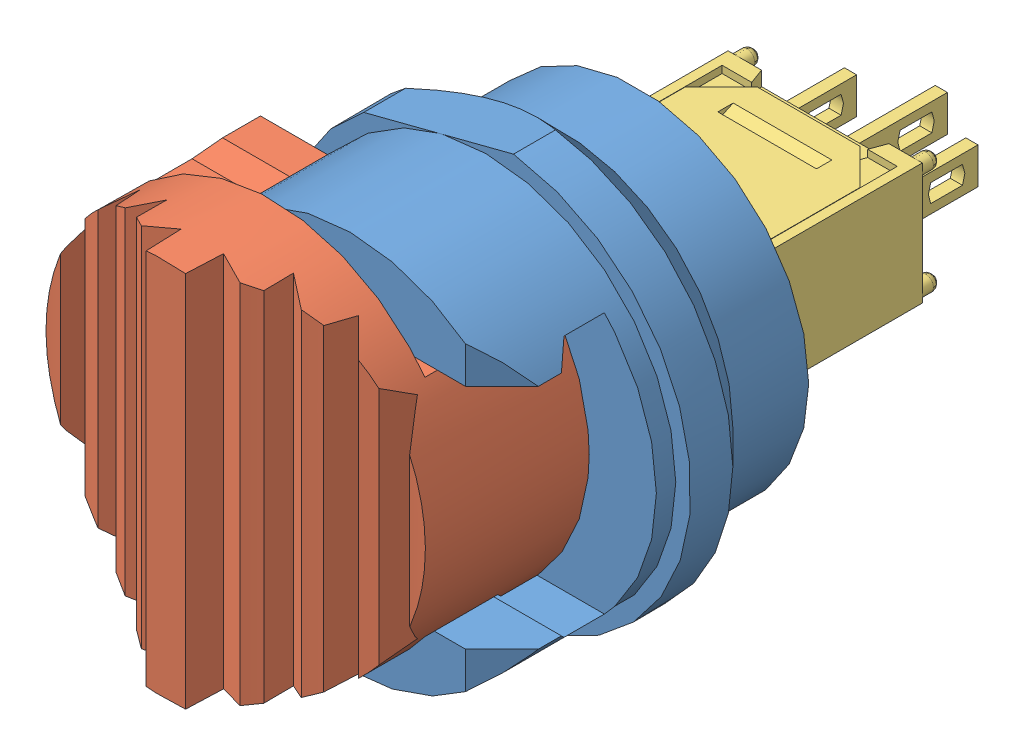
SolidWorks assembly DISPENSE Switch, configuration Default. Lengths in mm.
Overall size (19.33 17.7 29.64).
4 component instances, 4 part files, 9 mates.
Components (placement in the parent):
- SPD BRK Switch Body-1: SPD BRK Switch Body [Default] at origin size (17.14 17.7 12.04)
- SPD BRK Switch Cap-1: SPD BRK Switch Cap [Default] at (-2.8116 0 0) size (15.88 15.88 9.81)
- 200MSPxT1B1M1QE-1: 200MSPxT1B1M1QE [200MSP4T1B1M2REH] at (0 0 -12.6025) size (8.13 6 27)
- HDW211048UNSHEXNUT-1: HDW211048UNSHEXNUT [Default] at (0 0 -0.2675) x (-0.866025 -0.5 0) z (0.5 -0.866025 0) size (7 1.32 8.08)
Mates (geometry in assembly coordinates):
- Concentric1: concentric aligned: cylinder of SPD BRK Switch Body-1 through (0 0 -9.3345) axis (0 0 1) radius 7.1501; cylinder of 200MSPxT1B1M1QE-1 through (0 0 -5.022) axis (0 0 1) radius 2.3
- Coincident1: coincident anti-aligned: plane of SPD BRK Switch Body-1 through (-4.0005 0 -4.7625) normal (0 0 -1); plane of 200MSPxT1B1M1QE-1 through (3.3 -3.3 -4.7625) normal (0 0 1)
- Perpendicular1: perpendicular: plane of SPD BRK Switch Cap-1 through (-3.6371 0 12.1793) normal (-0.999133 0 0.041631); plane of 200MSPxT1B1M1QE-1 through (-4.065 2.54 -12.6025) normal (0 1 0)
- Width1: width anti-aligned: plane of SPD BRK Switch Cap-1 through (-2.8116 4.699 7.7343) normal (0 1 0); plane of SPD BRK Switch Body-1 through (-2.8116 -4.699 3.9243) normal (0 -1 0); plane of SPD BRK Switch Cap-1 through (0 4.7625 4.0259) normal (0 -1 0); plane of SPD BRK Switch Body-1 through (0 -4.7625 7.2771) normal (0 1 0)
- Coincident2: coincident anti-aligned: plane of SPD BRK Switch Body-1 through (0 -5.461 2.4003) normal (0 0 1); plane of SPD BRK Switch Cap-1 through (-2.8116 0 2.4003) normal (0 0 -1)
- Coincident3: coincident: line of SPD BRK Switch Cap-1 through (-2.8116 0 -7.3787) axis (0 0 1); point of 200MSPxT1B1M1QE-1
- Concentric2: concentric anti-aligned: cylinder of 200MSPxT1B1M1QE-1 through (0 0 -5.022) axis (0 0 1) radius 2.3; cylinder of HDW211048UNSHEXNUT-1 through (0 0 -0.2675) axis (0 0 -1) radius 2.413
- Parallel1: parallel anti-aligned: plane of SPD BRK Switch Body-1 through (-2.1264 -3.683 -14.4268) normal (0 1 0); plane of HDW211048UNSHEXNUT-1 through (2.0207 -3.5 -1.5875) normal (0 -1 0)
- Coincident4: coincident anti-aligned: plane of SPD BRK Switch Body-1 through (8.5725 0 -1.5875) normal (0 0 1); plane of HDW211048UNSHEXNUT-1 through (0 0 -1.5875) normal (0 0 -1)
